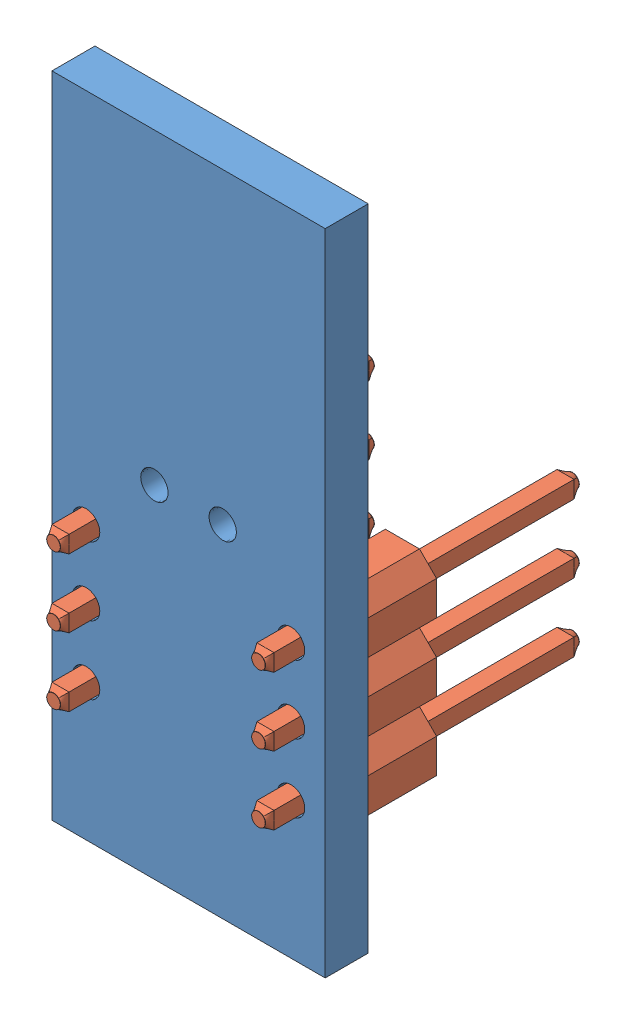
SolidWorks assembly SparkFun LiPo Fuel Gauge TOL-10617, configuration Default. Lengths in mm.
Overall size (10.16 24.13 11.76).
9 component instances, 2 part files, 6 mates.
Components (placement in the parent):
- lipo_fuel_gaugev11-1: lipo_fuel_gaugev11 [Default] at origin size (10.16 24.13 1.6)
- Male Header 3 Pin-2: Male Header 3 Pin [Default] at (1.5047 4.0786 -2.8976) size (2.54 7.62 11.76)
  - Male Header Pin-1: Male Header Pin [Default] at (-0.2347 1.0014 0.3576) size (2.54 2.54 11.76)
  - Male Header Pin-2: Male Header Pin [Default] at (-0.2347 3.5414 0.3576) size (2.54 2.54 11.76)
  - Male Header Pin-3: Male Header Pin [Default] at (-0.2347 6.0814 0.3576) size (2.54 2.54 11.76)
- Male Header 3 Pin-3: Male Header 3 Pin [Default] at (9.1247 4.0786 -2.8976) size (2.54 7.62 11.76)
  - Male Header Pin-1: Male Header Pin [Default] at (-0.2347 1.0014 0.3576) size (2.54 2.54 11.76)
  - Male Header Pin-2: Male Header Pin [Default] at (-0.2347 3.5414 0.3576) size (2.54 2.54 11.76)
  - Male Header Pin-3: Male Header Pin [Default] at (-0.2347 6.0814 0.3576) size (2.54 2.54 11.76)
Mates (geometry in assembly coordinates):
- Coincident1: coincident anti-aligned: plane of lipo_fuel_gaugev11-1 through (0 24.13 0) normal (0 0 -1); plane of Male Header 3 Pin-2/Male Header Pin-3 through (2.54 11.43 0) normal (0 0 1)
- Concentric1: concentric aligned: circle of lipo_fuel_gaugev11-1; circle of Male Header 3 Pin-2/Male Header Pin-3
- Concentric2: concentric aligned: circle of lipo_fuel_gaugev11-1; circle of Male Header 3 Pin-2/Male Header Pin-1
- Coincident3: coincident anti-aligned: plane of lipo_fuel_gaugev11-1 through (0 24.13 0) normal (0 0 -1); plane of Male Header 3 Pin-3/Male Header Pin-3 through (10.16 11.43 0) normal (0 0 1)
- Concentric3: concentric aligned: circle of lipo_fuel_gaugev11-1; circle of Male Header 3 Pin-3/Male Header Pin-3
- Concentric4: concentric aligned: circle of lipo_fuel_gaugev11-1; circle of Male Header 3 Pin-3/Male Header Pin-1
